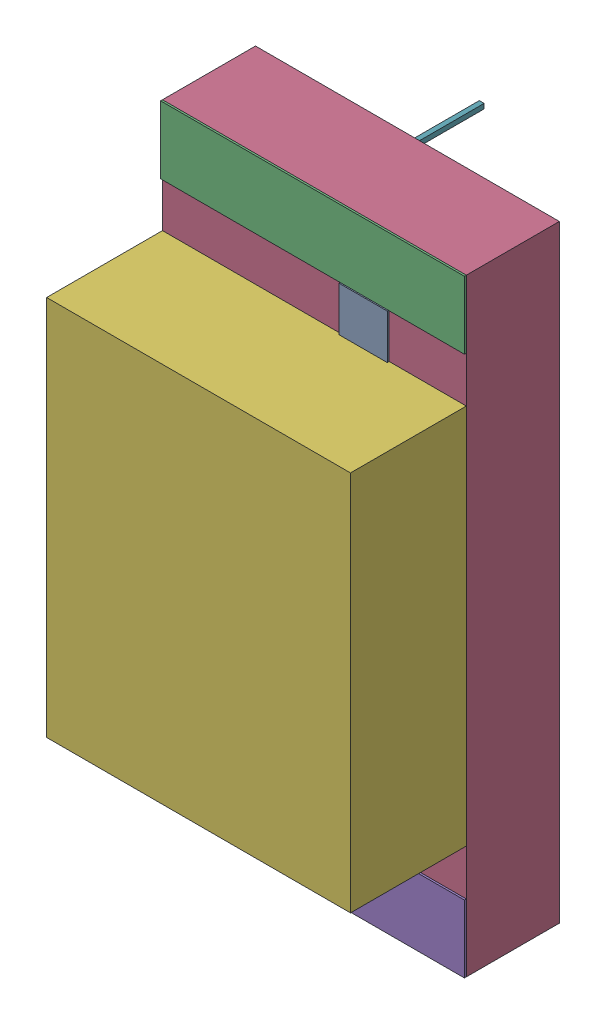
SolidWorks assembly Ddebug3, configuration Défaut. Lengths in mm.
Overall size (1.6 3.2 1.52).
15 component instances, 6 part files, 0 mates.
Components (placement in the parent):
- SW3dPS-LED1206G-1: SW3dPS-LED1206G [Défaut] at (41.6433 30.7086 0) x (0 -1 0) z (0 0 1) size (3.2 1.6 1.52)
  - SW3dPS-LED1206G_Open_CASCADE_STEP_translator_6.2_262.2-1: SW3dPS-LED1206G_Open_CASCADE_STEP_translator_6.2_262.2 [Défaut] at origin size (3.2 1.6 1.1)
    - SW3dPS-LED1206G_352699472-1: SW3dPS-LED1206G_352699472 [Défaut] at (0.6096 0.0254 0.5027) size (0.65 0.76 0.01)
      - SW3dPS-LED1206G_Extruded-1: SW3dPS-LED1206G_Extruded [Défaut] at origin size (0.65 0.76 0.01)
    - SW3dPS-LED1206G_352698192-1: SW3dPS-LED1206G_352698192 [Défaut] at (2.1971 0.0254 0.5027) size (1.14 0.76 0.01)
      - SW3dPS-LED1206G_Extruded4-1: SW3dPS-LED1206G_Extruded4 [Défaut] at origin size (1.14 0.76 0.01)
    - SW3dPS-LED1206G_352697808-1: SW3dPS-LED1206G_352697808 [Défaut] at (0.1016 0.0127 0.5027) size (0.36 1.6 0.01)
      - SW3dPS-LED1206G_Extruded2-1: SW3dPS-LED1206G_Extruded2 [Défaut] at origin size (0.36 1.6 0.01)
    - SW3dPS-LED1206G_352697936-1: SW3dPS-LED1206G_352697936 [Défaut] at (1.524 0.0127 0.0127) size (3.2 1.6 0.49)
      - SW3dPS-LED1206G_Extruded1-1: SW3dPS-LED1206G_Extruded1 [Défaut] at origin size (3.2 1.6 0.49)
    - SW3dPS-LED1206G_352697808-2: SW3dPS-LED1206G_352697808 [Défaut] at (2.9464 0.0127 0.5027) size (0.36 1.6 0.01)
      - SW3dPS-LED1206G_Extruded2-1: SW3dPS-LED1206G_Extruded2 [Défaut] at origin size (0.36 1.6 0.01)
    - SW3dPS-LED1206G_352700880-1: SW3dPS-LED1206G_352700880 [Défaut] at (1.524 0.0127 0.5027) size (2.01 1.6 0.61)
      - SW3dPS-LED1206G_Extruded3-1: SW3dPS-LED1206G_Extruded3 [Défaut] at origin size (2.01 1.6 0.61)
  - SW3dPS-LED1206G_Board-1: SW3dPS-LED1206G_Board [Défaut] at (0 0 -0.4039) size (0.03 0.03 0.42)
